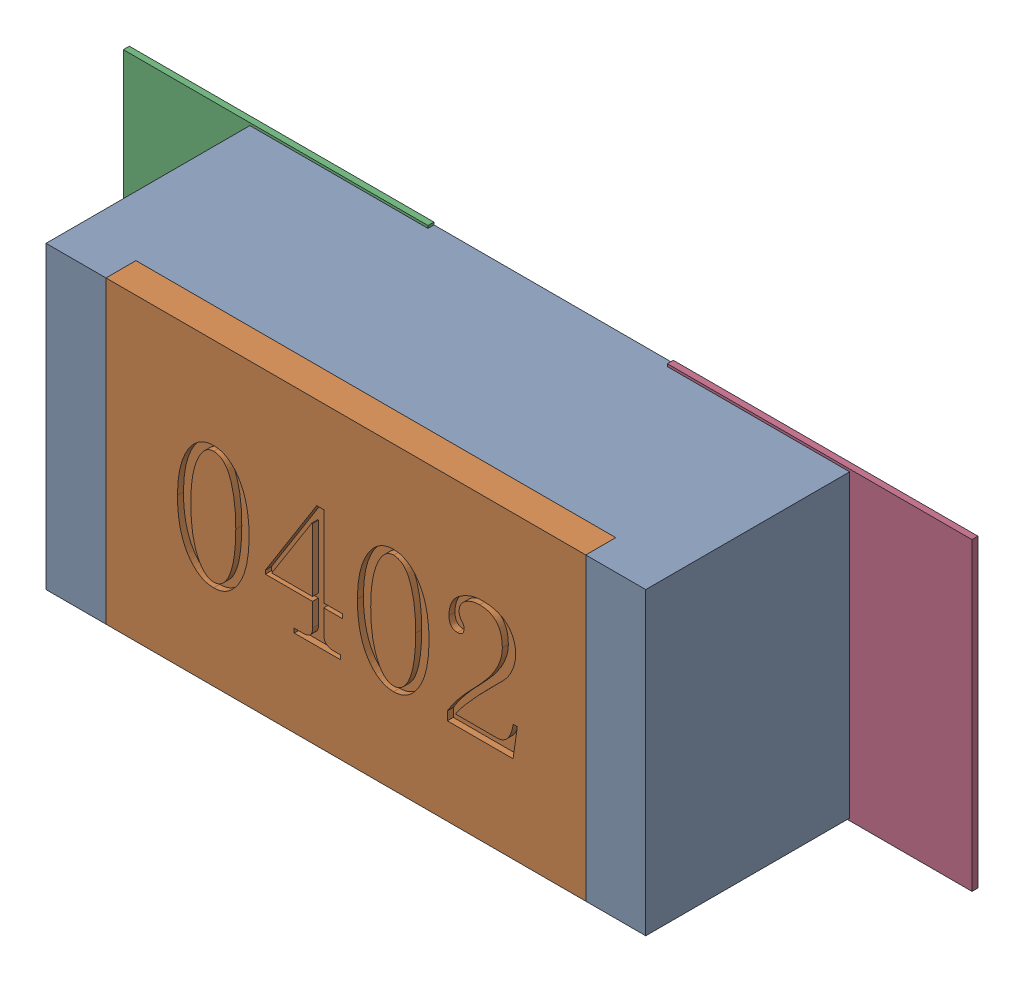
SolidWorks assembly R145, configuration Défaut. Lengths in mm.
Overall size (1.42 0.51 0.35).
5 component instances, 2 part files, 0 mates.
Components (placement in the parent):
- R0402-1: R0402 [Défaut] at (12.2936 -27.0257 0) x (1 0 0) z (0 0 1) size (1 0.5 0.35)
- 6504207776-1: 6504207776 [Défaut] at (11.8365 -27.0256 0) size (0.51 0.51 0.01)
  - Extruded-1: Extruded [Défaut] at origin size (0.51 0.51 0.01)
- 6504207776-2: 6504207776 [Défaut] at (12.7436 -27.0256 0) size (0.51 0.51 0.01)
  - Extruded-1: Extruded [Défaut] at origin size (0.51 0.51 0.01)
